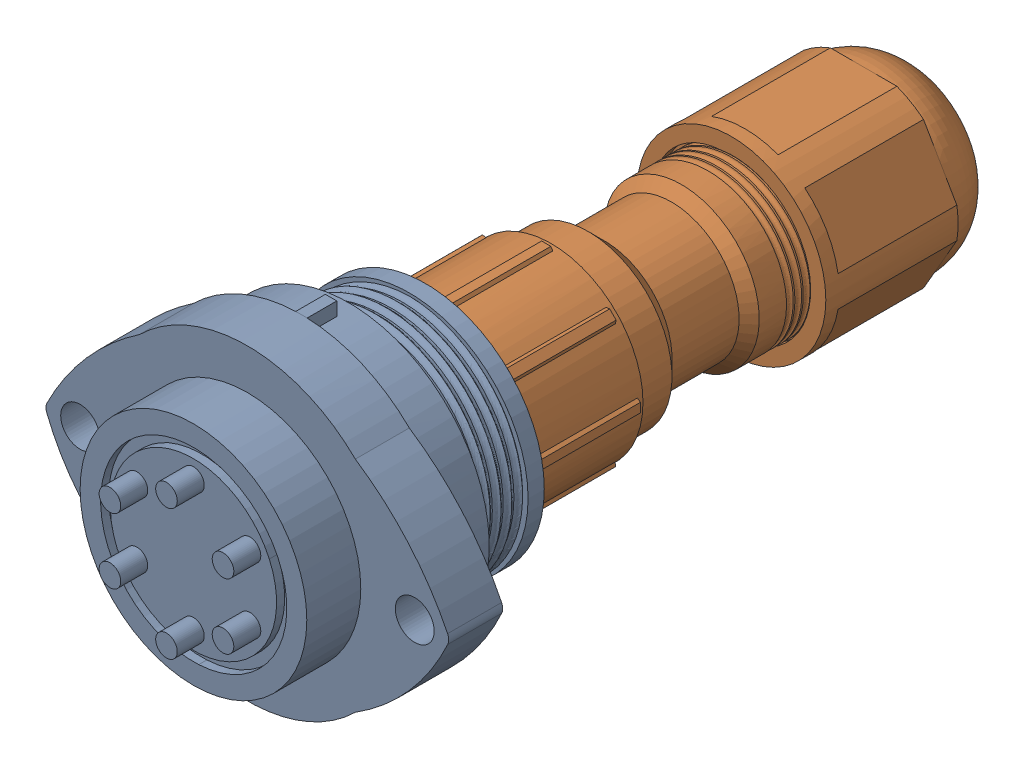
SolidWorks assembly 6 Pin Assembly, configuration Default. Lengths in mm.
Overall size (37.31 28.5 68.91).
2 component instances, 2 part files, 1 mates.
Components (placement in the parent):
- 6 pin connector-1: 6 pin connector [Default] at (15.7175 13.2613 -12.0499) size (37.31 28.5 25.5)
- 6 pin connector female part-1: 6 pin connector female part [Default] at (15.6108 13.0367 -30.2999) size (17.52 17.52 48.16)
Mates (geometry in assembly coordinates):
- Coincident2: coincident anti-aligned: plane of 6 pin connector-1 through (15.7175 16.6913 -27.0499) normal (0 0 -1); plane of 6 pin connector female part-1 through (15.6108 16.4667 -27.0499) normal (0 0 1)
